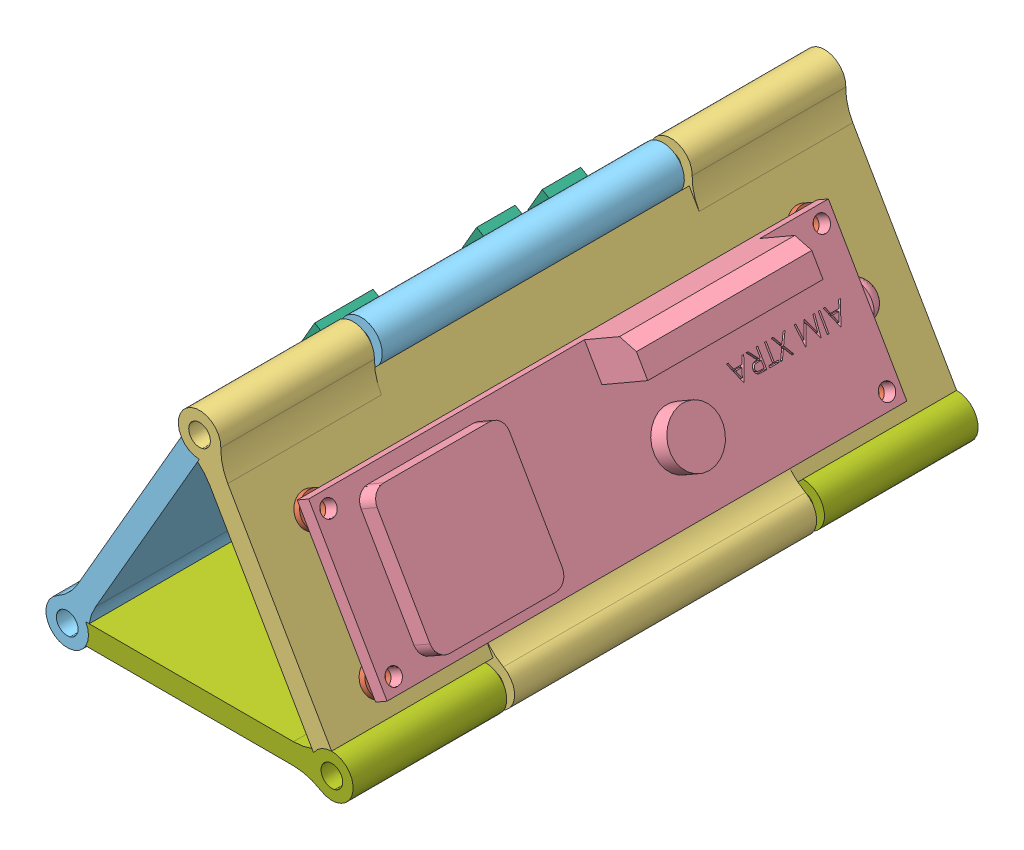
SolidWorks assembly Fight_Computer_Stack_Assy, configuration Default. Lengths in mm.
Overall size (74.68 77.18 120).
30 component instances, 8 part files, 70 mates.
Components (placement in the parent):
- 6.86mm_Nut_3mm_Hole-7: 6.86mm_Nut_3mm_Hole [Default] at (49.4605 62.5264 50.3494) x (0.433013 -0.75 0.5) z (-0.25 0.433013 0.866025) size (7.92 1.91 6.86)
- 6.86mm_Nut_3mm_Hole-10: 6.86mm_Nut_3mm_Hole [Default] at (38.5881 85.168 145.066) x (-0.433013 0.75 -0.5) z (-0.25 0.433013 0.866025) size (7.92 1.91 6.86)
- 6.86mm_Nut_3mm_Hole-11: 6.86mm_Nut_3mm_Hole [Default] at (36.9383 84.2155 50.3494) x (0.433013 -0.75 -0.5) z (0.25 -0.433013 0.866025) size (7.92 1.91 6.86)
- 6.86mm_Nut_3mm_Hole-12: 6.86mm_Nut_3mm_Hole [Default] at (49.4605 62.5264 145.066) x (0.433013 -0.75 -0.5) z (0.25 -0.433013 0.866025) size (7.92 1.91 6.86)
- Ruber_Washer_3mm-5: Ruber_Washer_3mm [Default] at (53.7083 64.9789 145.066) x (-0.5 0.866025 0) z (0 0 1) size (6 1.25 6)
- Ruber_Washer_3mm-6: Ruber_Washer_3mm [Default] at (41.1861 86.668 145.066) x (-0.5 0.866025 0) z (0 0 1) size (6 1.25 6)
- Ruber_Washer_3mm-7: Ruber_Washer_3mm [Default] at (53.7083 64.9789 50.3494) x (-0.5 0.866025 0) z (0 0 1) size (6 1.25 6)
- Ruber_Washer_3mm-8: Ruber_Washer_3mm [Default] at (41.1861 86.668 50.3494) x (-0.5 0.866025 0) z (0 0 1) size (6 1.25 6)
- Avionics_Stack - AIM-1: Avionics_Stack - AIM [Default] at (55.5493 84.6273 26.5774) x (-0.5 -0.866025 0) z (0 0 1) size (33.58 52.18 120)
- AimXtra-1: AimXtra [Default] at (39.9161 88.8677 47.8094) x (0 0 1) z (-0.5 0.866025 0) size (102.34 16.13 30.12)
- 6.86mm_Nut_3mm_Hole-4: 6.86mm_Nut_3mm_Hole [Default] at (13.2223 66.1787 125.5587) x (0.433013 0.75 -0.5) z (0.25 0.433013 0.866025) size (7.92 1.91 6.86)
- 6.86mm_Nut_3mm_Hole-5: 6.86mm_Nut_3mm_Hole [Default] at (24.7223 86.0973 125.5587) x (0.433013 0.75 -0.5) z (0.25 0.433013 0.866025) size (7.92 1.91 6.86)
- 6.86mm_Nut_3mm_Hole-6: 6.86mm_Nut_3mm_Hole [Default] at (13.2223 66.1787 69.0624) x (0.433013 0.75 0.5) z (-0.25 -0.433013 0.866025) size (7.92 1.91 6.86)
- 6.86mm_Nut_3mm_Hole-8: 6.86mm_Nut_3mm_Hole [Default] at (24.7223 86.0973 67.5587) x (0.433013 0.75 -0.5) z (0.25 0.433013 0.866025) size (7.92 1.91 6.86)
- Ruber_Washer_3mm-1: Ruber_Washer_3mm [Default] at (21.3404 88.0498 67.5587) x (0.5 0.866025 0) z (0 0 1) size (6 1.25 6)
- Ruber_Washer_3mm-2: Ruber_Washer_3mm [Default] at (9.8404 68.1312 69.0624) x (0.5 0.866025 0) z (0 0 1) size (6 1.25 6)
- Ruber_Washer_3mm-3: Ruber_Washer_3mm [Default] at (21.3404 88.0498 125.5587) x (0.5 0.866025 0) z (0 0 1) size (6 1.25 6)
- Ruber_Washer_3mm-4: Ruber_Washer_3mm [Default] at (9.8404 68.1312 125.5587) x (0.5 0.866025 0) z (0 0 1) size (6 1.25 6)
- Avionics_Stack-1: Avionics_Stack [Default] at (4.7361 84.6273 26.5774) size (33.58 52.18 120)
- RBP2W-1: RBP2W [Default] at (13.9471 81.3442 101.7819) x (0 0 -1) z (0.5 0.866025 0) size (65 5.1 31.05)
- 6.86mm_Nut_3mm_Hole-1: 6.86mm_Nut_3mm_Hole [Default] at (44.7248 57.1953 44.9616) x (-0.868623 0 -0.495473) z (-0.495473 0 0.868623) size (7.92 1.91 6.86)
- 6.86mm_Nut_3mm_Hole-2: 6.86mm_Nut_3mm_Hole [Default] at (44.7248 57.1953 59.1316) x (-0.868623 0 -0.495473) z (-0.495473 0 0.868623) size (7.92 1.91 6.86)
- 6.86mm_Nut_3mm_Hole-3: 6.86mm_Nut_3mm_Hole [Default] at (12.4948 57.1953 59.1316) x (-0.868623 0 -0.495473) z (-0.495473 0 0.868623) size (7.92 1.91 6.86)
- 6.86mm_Nut_3mm_Hole-9: 6.86mm_Nut_3mm_Hole [Default] at (12.4948 57.1953 44.9616) x (-0.855922 0 -0.517105) z (-0.517105 0 0.855922) size (7.92 1.91 6.86)
- Ruber_Washer_3mm-9: Ruber_Washer_3mm [Default] at (12.4948 52.0403 44.9616) size (6 1.25 6)
- Ruber_Washer_3mm-10: Ruber_Washer_3mm [Default] at (44.7248 52.0403 44.9616) size (6 1.25 6)
- Ruber_Washer_3mm-11: Ruber_Washer_3mm [Default] at (44.7248 52.0403 59.1316) size (6 1.25 6)
- Ruber_Washer_3mm-13: Ruber_Washer_3mm [Default] at (12.4948 52.0403 59.1316) size (6 1.25 6)
- Avionics_Stack - EasyMini-1: Avionics_Stack - EasyMini [Default] at (30.1427 40.6218 26.5774) x (-0.5 0.866025 0) z (0 0 1) size (33.58 52.18 120)
- EZMINI-1: EZMINI [Default] at (28.7345 50.2403 46.2994) x (1 0 0) z (0 0 -1) size (38.23 12.5 21.18)
Mates (geometry in assembly coordinates):
- Coincident12: coincident anti-aligned: plane of Avionics_Stack - EasyMini-1 through (30.1427 55.2903 26.5774) normal (0 1 0); plane of 6.86mm_Nut_3mm_Hole-3 through (12.4948 55.2903 59.1316) normal (0 -1 0)
- Concentric4: concentric anti-aligned: cylinder of Avionics_Stack - EasyMini-1 through (12.4948 61.5329 59.1316) axis (0 -1 0) radius 1.5; cylinder of 6.86mm_Nut_3mm_Hole-3 through (12.4948 55.2903 59.1316) axis (0 1 0) radius 1.5
- Concentric5: concentric anti-aligned: cylinder of Avionics_Stack - EasyMini-1 through (12.4948 61.5329 44.9616) axis (0 -1 0) radius 1.5; cylinder of 6.86mm_Nut_3mm_Hole-9 through (12.4948 55.2903 44.9616) axis (0 1 0) radius 1.5
- Coincident14: coincident anti-aligned: plane of Avionics_Stack - EasyMini-1 through (30.1427 55.2903 26.5774) normal (0 1 0); plane of 6.86mm_Nut_3mm_Hole-9 through (12.4948 55.2903 44.9616) normal (0 -1 0)
- Concentric6: concentric anti-aligned: cylinder of Avionics_Stack - EasyMini-1 through (44.7248 61.5329 59.1316) axis (0 -1 0) radius 1.5; cylinder of 6.86mm_Nut_3mm_Hole-2 through (44.7248 55.2903 59.1316) axis (0 1 0) radius 1.5
- Concentric7: concentric anti-aligned: cylinder of Avionics_Stack - EasyMini-1 through (44.7248 61.5329 44.9616) axis (0 -1 0) radius 1.5; cylinder of 6.86mm_Nut_3mm_Hole-1 through (44.7248 55.2903 44.9616) axis (0 1 0) radius 1.5
- Coincident15: coincident anti-aligned: plane of Avionics_Stack - EasyMini-1 through (30.1427 55.2903 26.5774) normal (0 1 0); plane of 6.86mm_Nut_3mm_Hole-2 through (44.7248 55.2903 59.1316) normal (0 -1 0)
- Coincident16: coincident anti-aligned: plane of Avionics_Stack - EasyMini-1 through (30.1427 55.2903 26.5774) normal (0 1 0); plane of 6.86mm_Nut_3mm_Hole-1 through (44.7248 55.2903 44.9616) normal (0 -1 0)
- Coincident17: coincident anti-aligned: plane of Avionics_Stack-1 through (17.4394 77.293 26.5774) normal (0.866025 -0.5 0); plane of 6.86mm_Nut_3mm_Hole-5 through (23.0725 87.0498 125.5587) normal (-0.866025 0.5 0)
- Coincident18: coincident anti-aligned: plane of Avionics_Stack-1 through (17.4394 77.293 26.5774) normal (0.866025 -0.5 0); plane of 6.86mm_Nut_3mm_Hole-4 through (11.5725 67.1312 125.5587) normal (-0.866025 0.5 0)
- Coincident19: coincident anti-aligned: plane of Avionics_Stack-1 through (17.4394 77.293 26.5774) normal (0.866025 -0.5 0); plane of 6.86mm_Nut_3mm_Hole-8 through (23.0725 87.0498 67.5587) normal (-0.866025 0.5 0)
- Coincident20: coincident anti-aligned: plane of Avionics_Stack-1 through (17.4394 77.293 26.5774) normal (0.866025 -0.5 0); plane of 6.86mm_Nut_3mm_Hole-6 through (11.5725 67.1312 69.0624) normal (-0.866025 0.5 0)
- Concentric8: concentric anti-aligned: circle of Avionics_Stack-1; cylinder of 6.86mm_Nut_3mm_Hole-8 through (23.0725 87.0498 67.5587) axis (0.866025 -0.5 0) radius 1.5
- Parallel2: parallel anti-aligned: line of Avionics_Stack-1 through (24.8045 86.0498 63.5993) axis (0.433013 0.75 0.5); line of 6.86mm_Nut_3mm_Hole-8 through (26.4373 89.0677 65.5784) axis (-0.433013 -0.75 -0.5)
- Concentric9: concentric anti-aligned: cylinder of Avionics_Stack-1 through (18.2035 63.3027 69.0624) axis (-0.866025 0.5 0) radius 2; cylinder of 6.86mm_Nut_3mm_Hole-6 through (11.5725 67.1312 69.0624) axis (0.866025 -0.5 0) radius 1.5
- Parallel3: parallel anti-aligned: line of Avionics_Stack-1 through (13.3045 66.1312 65.103) axis (0.433013 0.75 0.5); line of 6.86mm_Nut_3mm_Hole-6 through (14.9373 69.1491 67.0821) axis (-0.433013 -0.75 -0.5)
- Concentric10: concentric anti-aligned: circle of Avionics_Stack-1; cylinder of 6.86mm_Nut_3mm_Hole-4 through (11.5725 67.1312 125.5587) axis (0.866025 -0.5 0) radius 1.5
- Parallel4: parallel anti-aligned: line of Avionics_Stack-1 through (13.3045 66.1312 129.5182) axis (-0.433013 -0.75 -0.5); line of 6.86mm_Nut_3mm_Hole-4 through (11.5073 63.2082 127.539) axis (0.433013 0.75 0.5)
- Concentric11: concentric anti-aligned: cylinder of Avionics_Stack-1 through (29.7035 83.2213 125.5587) axis (-0.866025 0.5 0) radius 2; cylinder of 6.86mm_Nut_3mm_Hole-5 through (23.0725 87.0498 125.5587) axis (0.866025 -0.5 0) radius 1.5
- Parallel5: parallel anti-aligned: line of Avionics_Stack-1 through (26.519 89.0194 127.5385) axis (-0.433013 -0.75 0.5); line of 6.86mm_Nut_3mm_Hole-5 through (24.7223 86.0973 129.5193) axis (0.433013 0.75 -0.5)
- Coincident29: coincident anti-aligned: plane of Avionics_Stack - AIM-1 through (43.0625 77.418 26.5774) normal (-0.866025 -0.5 0); plane of 6.86mm_Nut_3mm_Hole-11 through (38.5881 85.168 50.3494) normal (0.866025 0.5 0)
- Coincident30: coincident anti-aligned: plane of Avionics_Stack - AIM-1 through (43.0625 77.418 26.5774) normal (-0.866025 -0.5 0); plane of 6.86mm_Nut_3mm_Hole-12 through (51.1103 63.4789 145.066) normal (0.866025 0.5 0)
- Coincident31: coincident anti-aligned: plane of Avionics_Stack - AIM-1 through (43.0625 77.418 26.5774) normal (-0.866025 -0.5 0); plane of 6.86mm_Nut_3mm_Hole-7 through (51.1103 63.4789 50.3494) normal (0.866025 0.5 0)
- Coincident32: coincident anti-aligned: plane of Avionics_Stack - AIM-1 through (43.0625 77.418 26.5774) normal (-0.866025 -0.5 0); plane of 6.86mm_Nut_3mm_Hole-10 through (38.5881 85.168 145.066) normal (0.866025 0.5 0)
- Concentric13: concentric anti-aligned: circle of Avionics_Stack - AIM-1; cylinder of 6.86mm_Nut_3mm_Hole-12 through (51.1103 63.4789 145.066) axis (-0.866025 -0.5 0) radius 1.5
- Concentric14: concentric anti-aligned: cylinder of Avionics_Stack - AIM-1 through (32.3529 81.5681 145.066) axis (0.866025 0.5 0) radius 1.75; circle of 6.86mm_Nut_3mm_Hole-10
- Concentric15: concentric aligned: circle of Avionics_Stack - AIM-1; circle of 6.86mm_Nut_3mm_Hole-11
- Concentric16: concentric aligned: circle of Avionics_Stack - AIM-1; circle of 6.86mm_Nut_3mm_Hole-7
- Parallel6: parallel anti-aligned: line of Avionics_Stack - AIM-1 through (47.4472 65.3235 48.3696) axis (0.433013 -0.75 -0.5); line of 6.86mm_Nut_3mm_Hole-7 through (49.4605 62.5264 46.3887) axis (-0.433013 0.75 0.5)
- Parallel7: parallel anti-aligned: line of Avionics_Stack - AIM-1 through (34.925 87.0126 48.3696) axis (0.433013 -0.75 -0.5); line of 6.86mm_Nut_3mm_Hole-11 through (36.9383 84.2155 46.3887) axis (-0.433013 0.75 0.5)
- Parallel8: parallel aligned: line of Avionics_Stack - AIM-1 through (34.925 87.0126 147.0457) axis (0 0 -1); line of 6.86mm_Nut_3mm_Hole-10 through (35.2233 87.186 147.0463) axis (0 0 -1)
- Parallel9: parallel anti-aligned: line of Avionics_Stack - AIM-1 through (49.1617 62.3539 149.0254) axis (-0.433013 0.75 -0.5); line of 6.86mm_Nut_3mm_Hole-12 through (47.7455 65.4969 147.0463) axis (0.433013 -0.75 0.5)
- Concentric17: concentric aligned: cylinder of Avionics_Stack - AIM-1 through (55.5493 55.2903 156.5774) axis (0 0 -1) radius 2.0875; cylinder of Avionics_Stack - EasyMini-1 through (55.5493 55.2903 156.5774) axis (0 0 -1) radius 2.0875
- Coincident37: coincident anti-aligned: cylinder of Avionics_Stack-1 through (4.7361 55.2903 156.5774) axis (0 0 -1) radius 2.0875; circle of Avionics_Stack - EasyMini-1
- Concentric18: concentric aligned: cylinder of Avionics_Stack - AIM-1 through (30.1427 99.2958 156.5774) axis (0 0 -1) radius 2.0875; cylinder of Avionics_Stack-1 through (30.1427 99.2958 156.5774) axis (0 0 -1) radius 2.0875
- Coincident40: coincident aligned: plane of Ruber_Washer_3mm-1 through (21.3404 88.0498 67.5587) normal (0.866025 -0.5 0); plane of Ruber_Washer_3mm-3 through (21.3404 88.0498 125.5587) normal (0.866025 -0.5 0)
- Coincident41: coincident aligned: plane of Ruber_Washer_3mm-2 through (9.8404 68.1312 69.0624) normal (0.866025 -0.5 0); plane of Ruber_Washer_3mm-4 through (9.8404 68.1312 125.5587) normal (0.866025 -0.5 0)
- Coincident42: coincident aligned: plane of Ruber_Washer_3mm-3 through (21.3404 88.0498 125.5587) normal (0.866025 -0.5 0); plane of Ruber_Washer_3mm-4 through (9.8404 68.1312 125.5587) normal (0.866025 -0.5 0)
- Coincident43: coincident anti-aligned: plane of Avionics_Stack-1 through (15.7074 78.293 156.5774) normal (-0.866025 0.5 0); plane of Ruber_Washer_3mm-4 through (9.8404 68.1312 125.5587) normal (0.866025 -0.5 0)
- Concentric19: concentric aligned: circle of Avionics_Stack-1; circle of Ruber_Washer_3mm-1
- Concentric20: concentric aligned: circle of Avionics_Stack-1; circle of Ruber_Washer_3mm-3
- Concentric21: concentric aligned: circle of Avionics_Stack-1; circle of Ruber_Washer_3mm-4
- Concentric22: concentric aligned: circle of Avionics_Stack-1; circle of Ruber_Washer_3mm-2
- Concentric26: concentric anti-aligned: cylinder of RBP2W-1 through (8.7579 68.7562 125.5587) axis (-0.866025 0.5 0) radius 1.5; cylinder of Ruber_Washer_3mm-4 through (8.7579 68.7562 125.5587) axis (0.866025 -0.5 0) radius 1.55
- Coincident46: coincident anti-aligned: plane of RBP2W-1 through (15.506 80.4442 101.7819) normal (0.866025 -0.5 0); plane of Ruber_Washer_3mm-1 through (20.2579 88.6748 67.5587) normal (-0.866025 0.5 0)
- Concentric27: concentric aligned: cylinder of Avionics_Stack-1 through (29.7035 83.2213 67.5587) axis (-0.866025 0.5 0) radius 2; circle of RBP2W-1
- Coincident47: coincident aligned: plane of Ruber_Washer_3mm-7 through (53.7083 64.9789 50.3494) normal (0.866025 0.5 0); plane of Ruber_Washer_3mm-8 through (41.1861 86.668 50.3494) normal (0.866025 0.5 0)
- Coincident48: coincident aligned: plane of Ruber_Washer_3mm-5 through (53.7083 64.9789 145.066) normal (0.866025 0.5 0); plane of Ruber_Washer_3mm-6 through (41.1861 86.668 145.066) normal (0.866025 0.5 0)
- Coincident49: coincident aligned: plane of Ruber_Washer_3mm-6 through (41.1861 86.668 145.066) normal (0.866025 0.5 0); plane of Ruber_Washer_3mm-7 through (53.7083 64.9789 50.3494) normal (0.866025 0.5 0)
- Coincident50: coincident anti-aligned: plane of Avionics_Stack - AIM-1 through (44.5781 78.293 156.5774) normal (0.866025 0.5 0); plane of Ruber_Washer_3mm-8 through (40.1036 86.043 50.3494) normal (-0.866025 -0.5 0)
- Concentric28: concentric anti-aligned: circle of Avionics_Stack - AIM-1; circle of Ruber_Washer_3mm-8
- Concentric29: concentric anti-aligned: circle of Avionics_Stack - AIM-1; circle of Ruber_Washer_3mm-7
- Concentric30: concentric anti-aligned: circle of Avionics_Stack - AIM-1; circle of Ruber_Washer_3mm-6
- Concentric31: concentric anti-aligned: circle of Avionics_Stack - AIM-1; circle of Ruber_Washer_3mm-5
- Concentric32: concentric aligned: cylinder of Avionics_Stack - AIM-1 through (32.3529 81.5681 50.3494) axis (0.866025 0.5 0) radius 1.75; cylinder of AimXtra-1 through (43.3858 87.938 50.3494) axis (0.866025 0.5 0) radius 1.5
- Coincident55: coincident anti-aligned: plane of AimXtra-1 through (39.9161 88.8677 47.8094) normal (-0.866025 -0.5 0); plane of Ruber_Washer_3mm-6 through (41.1861 86.668 145.066) normal (0.866025 0.5 0)
- Concentric33: concentric aligned: cylinder of Avionics_Stack - AIM-1 through (44.8751 59.879 145.066) axis (0.866025 0.5 0) radius 1.75; cylinder of AimXtra-1 through (55.908 66.2489 145.066) axis (0.866025 0.5 0) radius 1.5
- Coincident56: coincident aligned: plane of Ruber_Washer_3mm-10 through (44.7248 53.2903 44.9616) normal (0 1 0); plane of Ruber_Washer_3mm-11 through (44.7248 53.2903 59.1316) normal (0 1 0)
- Coincident57: coincident aligned: plane of Ruber_Washer_3mm-9 through (12.4948 53.2903 44.9616) normal (0 1 0); plane of Ruber_Washer_3mm-13 through (12.4948 53.2903 59.1316) normal (0 1 0)
- Coincident58: coincident aligned: circle of Ruber_Washer_3mm-9; plane of Ruber_Washer_3mm-11 through (44.7248 53.2903 59.1316) normal (0 1 0)
- Coincident59: coincident anti-aligned: plane of Avionics_Stack - EasyMini-1 through (30.1427 53.2903 156.5774) normal (0 -1 0); plane of Ruber_Washer_3mm-11 through (44.7248 53.2903 59.1316) normal (0 1 0)
- Concentric34: concentric anti-aligned: circle of Avionics_Stack - EasyMini-1; circle of Ruber_Washer_3mm-10
- Concentric35: concentric anti-aligned: circle of Avionics_Stack - EasyMini-1; circle of Ruber_Washer_3mm-11
- Concentric36: concentric anti-aligned: circle of Avionics_Stack - EasyMini-1; circle of Ruber_Washer_3mm-13
- Concentric37: concentric anti-aligned: circle of Avionics_Stack - EasyMini-1; circle of Ruber_Washer_3mm-9
- Concentric38: concentric aligned: cylinder of EZMINI-1 through (44.7248 52.0403 59.1316) axis (0 -1 0) radius 1.5; cylinder of Ruber_Washer_3mm-11 through (44.7248 53.2903 59.1316) axis (0 -1 0) radius 1.55
- Coincident60: coincident anti-aligned: plane of EZMINI-1 through (28.7345 52.0403 46.2994) normal (0 1 0); plane of Ruber_Washer_3mm-9 through (12.4948 52.0403 44.9616) normal (0 -1 0)
- Concentric39: concentric aligned: cylinder of EZMINI-1 through (12.4948 52.0403 44.9616) axis (0 -1 0) radius 1.5; cylinder of Ruber_Washer_3mm-9 through (12.4948 53.2903 44.9616) axis (0 -1 0) radius 1.55
- Coincident61: coincident aligned: plane of Avionics_Stack-1 through (4.7361 84.6273 156.5774) normal (0 0 1); plane of Avionics_Stack - EasyMini-1 through (30.1427 40.6218 156.5774) normal (0 0 1)
- Coincident62: coincident aligned: plane of Avionics_Stack - AIM-1 through (55.5493 84.6273 156.5774) normal (0 0 1); plane of Avionics_Stack-1 through (4.7361 84.6273 156.5774) normal (0 0 1)
